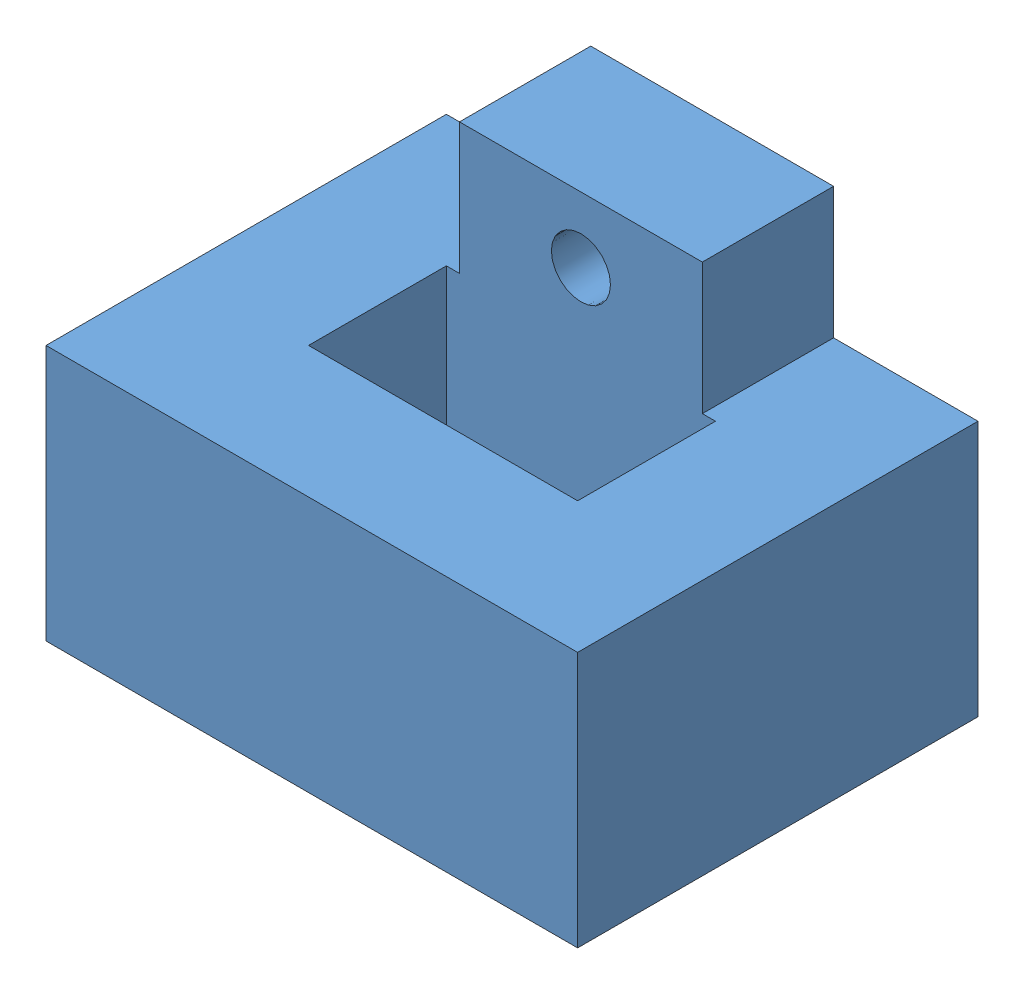
SolidWorks assembly Current Sensor, configuration Default. Lengths in mm.
Overall size (40.5 37.9 33.5).
2 component instances, 2 part files, 4 mates.
Components (placement in the parent):
- Current Sensor-1: Current Sensor [Default] at (6.4062 10.8288 34.1651) size (40.5 29.5 33.5)
- Current Sensor Connector-1: Current Sensor Connector [Default] at (-8.8938 12.4788 34.1651) x (0 0 1) z (1 0 0) size (9.5 15.1 5.8)
Mates (geometry in assembly coordinates):
- Coincident1: coincident: plane of Current Sensor-1 through (6.4062 10.8288 34.1651) normal (0 -1 0); plane of Current Sensor Connector-1 through (-21.4104 10.8288 29.4151) normal (0 -1 0)
- Parallel1: parallel: plane of Current Sensor-1 through (-13.8438 30.3288 18.9151) normal (0 0 -1); plane of Current Sensor Connector-1 through (-18.5604 12.4788 29.4151) normal (0 0 -1)
- Coincident3: coincident: plane of Current Sensor-1 through (6.4062 10.8288 34.1651) normal (0 0 1); plane of Current Sensor Connector-1
- Distance1: distance = 2.1 mm aligned: plane of Current Sensor Connector-1 through (-5.9438 10.8288 29.4151) normal (1 0 0); plane of Current Sensor-1 through (-3.8438 30.3288 28.9151) normal (1 0 0)
